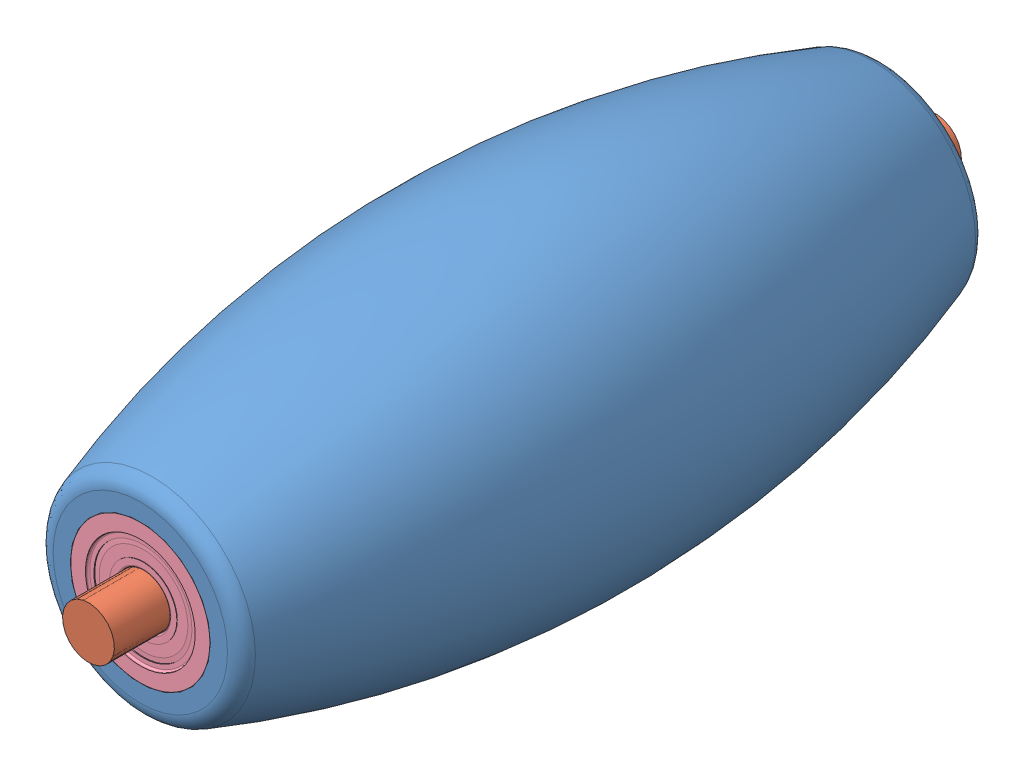
SolidWorks assembly Roller Assembly, configuration Default. Lengths in mm.
Overall size (11.4 11.4 29.4).
5 component instances, 4 part files, 11 mates.
Components (placement in the parent):
- Roller-1: Roller [Default] at origin size (11.4 11.4 25.8)
- Shaft-1: Shaft [Default] x (0.830924 -0.556385 0) z (-0.556385 -0.830924 0) size (1.8 29.4 1.8)
- Roller Suport-1: Roller Suport [Default] at origin size (5.4 5.4 24.84)
- Bearing-1: Bearing [Default] at (0 0 -13.4018) x (0 0 1) z (-1 0 0) size (1.9 4.86 4.86)
- Bearing-2: Bearing [Default] at (0 0 13.4018) x (0 0 -1) z (0.923728 0.383049 0) size (1.9 4.86 4.86)
Mates (geometry in assembly coordinates):
- Concentric1: concentric aligned: cylinder of DDMW Roller-1 through (0 0 12.9) axis (0 0 1) radius 2.7; cylinder of DDMW Roller Suport-1 through (0 0 10.158) axis (0 0 1) radius 2.7
- Concentric2: concentric aligned: cylinder of DDMW Roller Suport-1 through (0 0 10.158) axis (0 0 1) radius 2.1; cylinder of W 638_3 R-2RS1-2 through (0 0 -17.1) axis (0 0 1) radius 2.1
- Coincident2: coincident anti-aligned: plane of DDMW Roller Suport-1 through (0 2.7 12.42) normal (0 0 1); plane of W 638_3 R-2RS1-2 through (-0.8044 1.9398 12.42) normal (0 0 -1)
- Concentric3: concentric anti-aligned: cylinder of DDMW Roller Suport-1 through (0 0 10.158) axis (0 0 1) radius 2.1; cylinder of W 638_3 R-2RS1-1 through (0 0 17.1) axis (0 0 -1) radius 2.1
- Coincident3: coincident anti-aligned: plane of DDMW Roller Suport-1 through (0 2.7 -12.42) normal (0 0 -1); plane of W 638_3 R-2RS1-1 through (0 2.1 -12.42) normal (0 0 1)
- Coincident4: coincident aligned: plane of DDMW Roller-1 through (0 3.45 -12.9) normal (0 0 -1); plane of W 638_3 R-2RS1-1 through (0 2.41 -12.9) normal (0 0 -1)
- Concentric4: concentric anti-aligned: cylinder of DDMW Roller Shaft-1 through (0 0 14.7) axis (0 0 -1) radius 0.9; cylinder of W 638_3 R-2RS1-2 through (0 0 11.9018) axis (0 0 1) radius 0.9
- Coincident5: coincident aligned: plane of DDMW Roller-1 through (0 0 0) normal (0 0 1)
- Coincident6: coincident aligned: plane of DDMW Roller-1 through (0 0 0) normal (0 1 0)
- Coincident7: coincident aligned: plane of DDMW Roller-1 through (0 0 0) normal (1 0 0)
- Coincident8: coincident aligned: plane of DDMW Roller Shaft-1 through (0 0 0) normal (0 0 1)
